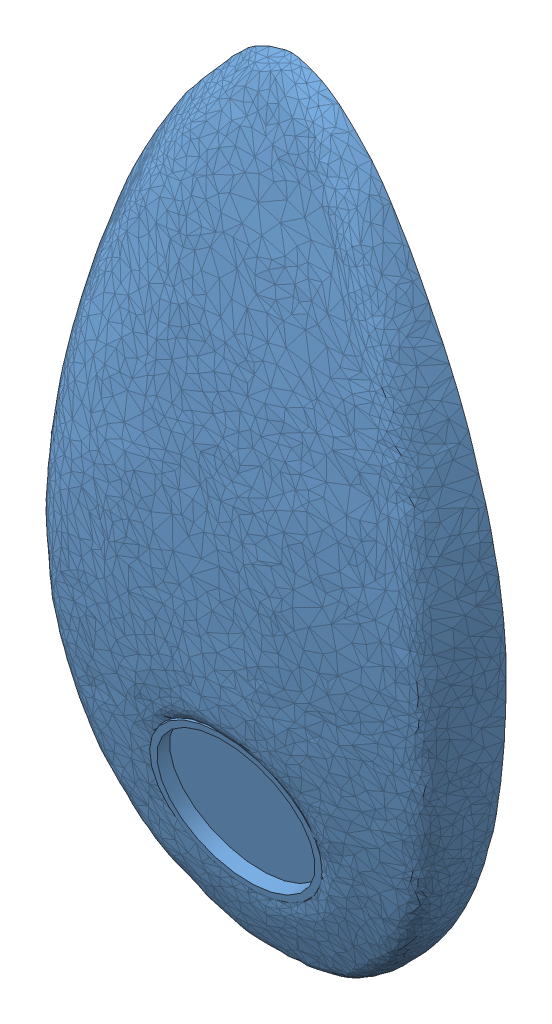
SolidWorks assembly Assem7, configuration Default. Lengths in mm.
Overall size (73.62 119.76 19.62).
2 component instances, 2 part files, 4 mates.
Components (placement in the parent):
- part_housingPrepared-1: part_housingPrepared [Default] at (1.4093 9.2175 -30.0595) size (64.09 119.76 15.04)
- housing-1: housing [Default] at (4.9432 -42.7892 -7.0078) x (0.412921 0.910384 0.026415) z (-0.904021 0.406167 0.133324) size (60.5 8.65 49)
Mates (geometry in assembly coordinates):
- Parallel1: parallel: plane of part_housingPrepared-1 through (-1.6251 -37.4771 -0.2238) normal (0.037263 -0.23582 0.971082); plane of housing-1 through (-10.0529 4.1324 7.6992) normal (0.037263 -0.23582 0.971082)
- Coincident2: coincident: plane of part_housingPrepared-1 through (-1.6251 -37.4771 -0.2238) normal (0.037263 -0.23582 0.971082); line of housing-1 through (-25.3288 4.1968 10.8059) axis (0.904021 -0.406167 -0.133324)
- Parallel2: parallel: line of part_housingPrepared-1 through (7.524 -35.4721 3.6208) axis (-0.904021 0.406167 0.133324); line of housing-1 through (-25.3288 4.1968 10.8059) axis (0.904021 -0.406167 -0.133324)
- Coincident4: coincident: line of part_housingPrepared-1 through (-1.4909 -38.3264 3.2736) axis (-0.037263 0.23582 -0.971082); point of housing-1
